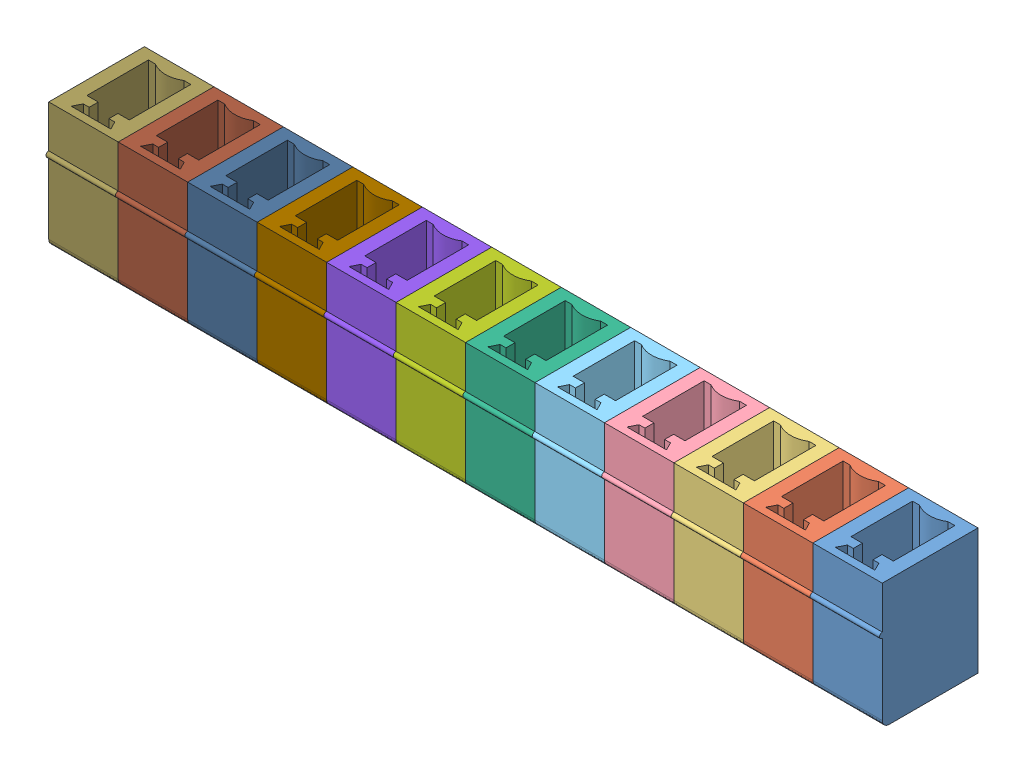
SolidWorks assembly PUTM-G-AM-BB-PCB-Connector-v2, configuration Domyślna. Lengths in mm.
Overall size (60.96 9.2 7.2).
25 component instances, 13 part files, 0 mates.
Components (placement in the parent):
- 15EDGRC-5.08- 12P-14-00A(H).stp-1: 15EDGRC-5.08- 12P-14-00A(H).stp [Domyślna] at origin size (60.96 9.2 10.6)
  - body_1pc.stp-1: body_1pc.stp [Domyślna] at origin size (5.08 9.2 7.2)
  - contact.stp-1: contact.stp [Domyślna] at (0.0085 0 0) size (0.8 6.77 7.1) (hidden)
  - body_1pc_1.stp-1: body_1pc_1.stp [Domyślna] at (-5.08 0 0) size (5.08 9.2 7.2)
  - contact.stp-2: contact.stp [Domyślna] at (-5.0715 0 0) size (0.8 6.77 7.1) (hidden)
  - body_1pc_2.stp-1: body_1pc_2.stp [Domyślna] at (-10.16 0 0) size (5.08 9.2 7.2)
  - contact.stp-3: contact.stp [Domyślna] at (-10.1515 0 0) size (0.8 6.77 7.1) (hidden)
  - body_1pc_3.stp-1: body_1pc_3.stp [Domyślna] at (-15.24 0 0) size (5.08 9.2 7.2)
  - contact.stp-4: contact.stp [Domyślna] at (-15.2315 0 0) size (0.8 6.77 7.1) (hidden)
  - body_1pc_4.stp-1: body_1pc_4.stp [Domyślna] at (-20.32 0 0) size (5.08 9.2 7.2)
  - contact.stp-5: contact.stp [Domyślna] at (-20.3115 0 0) size (0.8 6.77 7.1) (hidden)
  - body_1pc_5.stp-1: body_1pc_5.stp [Domyślna] at (-25.4 0 0) size (5.08 9.2 7.2)
  - contact.stp-6: contact.stp [Domyślna] at (-25.3915 0 0) size (0.8 6.77 7.1) (hidden)
  - body_1pc_6.stp-1: body_1pc_6.stp [Domyślna] at (-30.48 0 0) size (5.08 9.2 7.2)
  - contact.stp-7: contact.stp [Domyślna] at (-30.4715 0 0) size (0.8 6.77 7.1) (hidden)
  - body_1pc_7.stp-1: body_1pc_7.stp [Domyślna] at (-35.56 0 0) size (5.08 9.2 7.2)
  - contact.stp-8: contact.stp [Domyślna] at (-35.5515 0 0) size (0.8 6.77 7.1) (hidden)
  - body_1pc_8.stp-1: body_1pc_8.stp [Domyślna] at (-40.64 0 0) size (5.08 9.2 7.2)
  - contact.stp-9: contact.stp [Domyślna] at (-40.6315 0 0) size (0.8 6.77 7.1) (hidden)
  - body_1pc_9.stp-1: body_1pc_9.stp [Domyślna] at (-45.72 0 0) size (5.08 9.2 7.2)
  - contact.stp-10: contact.stp [Domyślna] at (-45.7115 0 0) size (0.8 6.77 7.1) (hidden)
  - body_1pc_10.stp-1: body_1pc_10.stp [Domyślna] at (-50.8 0 0) size (5.08 9.2 7.2)
  - contact.stp-11: contact.stp [Domyślna] at (-50.7915 0 0) size (0.8 6.77 7.1) (hidden)
  - body_1pc_11.stp-1: body_1pc_11.stp [Domyślna] at (-55.88 0 0) size (5.08 9.2 7.2)
  - contact.stp-12: contact.stp [Domyślna] at (-55.8715 0 0) size (0.8 6.77 7.1) (hidden)
